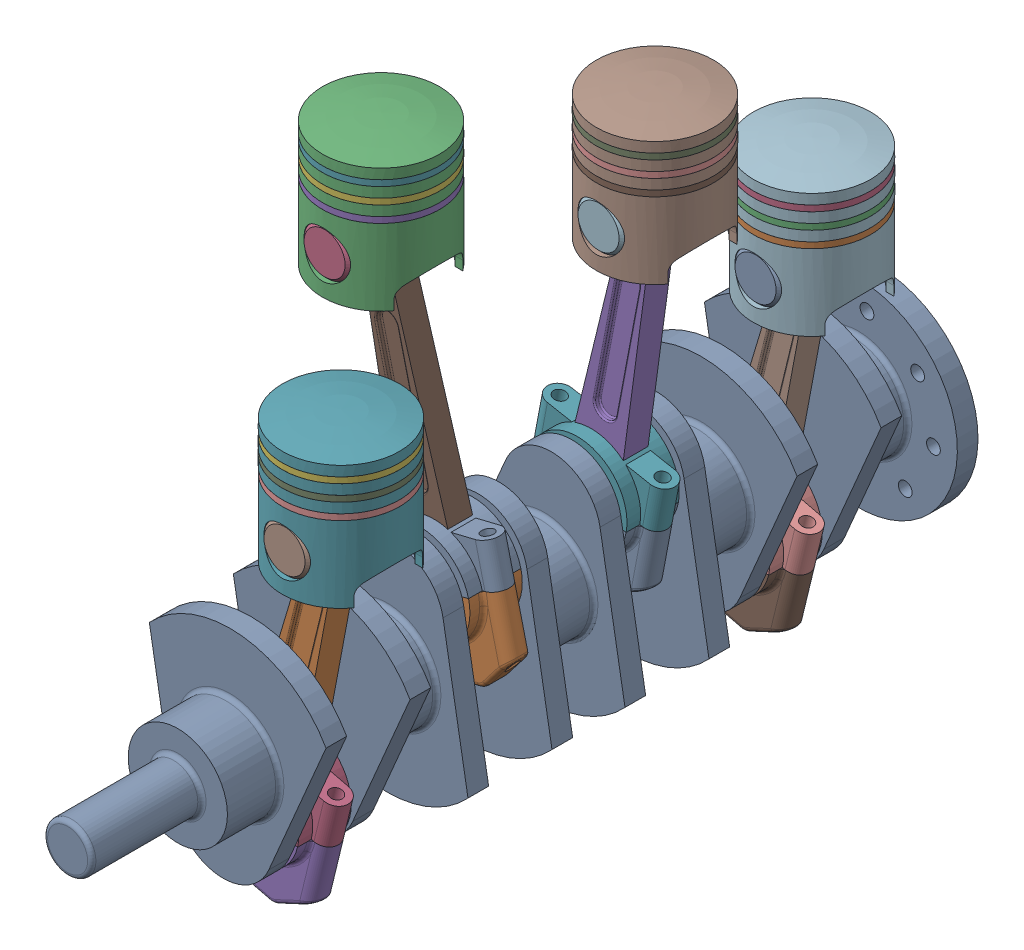
SolidWorks assembly engine, configuration Default. Lengths in mm.
Overall size (200.17 422.52 589).
29 component instances, 6 part files, 66 mates.
Components (placement in the parent):
- crankshaft-1: crankshaft [Default] at (0 0 454) x (0.993296 -0.115595 0) z (0 0 1) size (144 160 589)
- centerline-1: centerline [Default] at (42.4529 151.7981 431) x (0.971686 -0.236278 0) z (0 0 1) size (94 223.7 38)
- connecting rod cap-1: connecting rod cap [Default] at (-5.0862 -43.705 431) x (-0.971686 0.236278 0) z (0 0 1) size (94 60 38)
- engine ring-1: engine ring [Default] at (42.4529 203.1981 431) size (85 4.3 85)
- engine1-1: engine1 [Default] at (42.4529 124.7981 431) size (85 95 85)
- piston pin-1: piston pin [Default] at (42.4529 151.7981 431) size (33.8 33.8 82)
- engine ring-3: engine ring [Default] at (42.4529 191.5981 431) x (0.460546 0 -0.887636) z (0.887636 0 0.460546) size (85 4.3 85)
- engine ring-5: engine ring [Default] at (42.4529 179.9981 431) x (0.546944 0 -0.837169) z (0.837169 0 0.546944) size (85 4.3 85)
- centerline-3: centerline [Default] at (-42.4529 239.2082 317) x (0.971686 0.236278 0) z (0 0 1) size (94 223.7 38)
- connecting rod cap-3: connecting rod cap [Default] at (5.0862 43.705 317) x (-0.971686 -0.236278 0) z (0 0 1) size (94 60 38)
- engine1-3: engine1 [Default] at (-42.4529 212.2082 317) size (85 95 85)
- piston pin-3: piston pin [Default] at (-42.4529 239.2082 317) x (0.987351 0.158553 0) z (0 0 1) size (33.8 33.8 82)
- engine ring-6: engine ring [Default] at (-42.4529 267.4082 317) x (0.392049 0 -0.919944) z (0.919944 0 0.392049) size (85 4.3 85)
- engine ring-7: engine ring [Default] at (-42.4529 279.0082 317) x (0.298154 0 -0.954518) z (0.954518 0 0.298154) size (85 4.3 85)
- engine ring-8: engine ring [Default] at (-42.4529 290.6082 317) x (0.984578 0 -0.174947) z (0.174947 0 0.984578) size (85 4.3 85)
- centerline-9: centerline [Default] at (42.4529 151.7981 89) x (-0.971686 0.236278 0) z (0 0 -1) size (94 223.7 38)
- connecting rod cap-9: connecting rod cap [Default] at (-5.0862 -43.705 89) x (0.971686 -0.236278 0) z (0 0 -1) size (94 60 38)
- engine1-9: engine1 [Default] at (42.4529 124.7981 89) x (-1 0 0) z (0 0 -1) size (85 95 85)
- piston pin-9: piston pin [Default] at (42.4529 151.7981 89) x (-0.5 0.866025 0) z (0 0 -1) size (33.8 33.8 82)
- engine ring-24: engine ring [Default] at (42.4529 179.9981 89) x (-0.341569 0 -0.939857) z (0.939857 0 -0.341569) size (85 4.3 85)
- engine ring-25: engine ring [Default] at (42.4529 191.5981 89) x (-0.433781 0 -0.901018) z (0.901018 0 -0.433781) size (85 4.3 85)
- engine ring-26: engine ring [Default] at (42.4529 203.1981 89) x (0.6 0 -0.8) z (0.8 0 0.6) size (85 4.3 85)
- centerline-10: centerline [Default] at (42.4529 241.4047 203) x (-0.982603 0.185719 0) z (0 0 -1) size (94 223.7 38)
- engine1-10: engine1 [Default] at (42.4529 214.4047 203) x (-1 0 0) z (0 0 -1) size (85 95 85)
- engine ring-27: engine ring [Default] at (42.4529 292.8047 203) x (0.941458 0 -0.337131) z (0.337131 0 0.941458) size (85 4.3 85)
- engine ring-28: engine ring [Default] at (42.4529 281.2047 203) x (0.134335 0 -0.990936) z (0.990936 0 0.134335) size (85 4.3 85)
- engine ring-29: engine ring [Default] at (42.4529 269.6047 203) x (0.23269 0 -0.972551) z (0.972551 0 0.23269) size (85 4.3 85)
- piston pin-10: piston pin [Default] at (42.4529 241.4047 203) x (-0.173648 0.984808 0) z (0 0 -1) size (33.8 33.8 82)
- connecting rod cap-10: connecting rod cap [Default] at (5.0862 43.705 203) x (0.982603 -0.185719 0) z (0 0 -1) size (94 60 38)
Mates (geometry in assembly coordinates):
- Concentric1: concentric anti-aligned: cylinder of crankshaft-1 through (0 0 586.9999) axis (0 0 -1) radius 17.5
- Coincident2: coincident: plane of crankshaft-1 through (0 0 586.9999) normal (0 0 1)
- Coincident3: coincident aligned: plane of engine1-1 through (42.4529 124.8201 430.9999) normal (0 0 1); plane of piston pin-1 through (42.4529 151.8201 430.9999) normal (0 0 1)
- Concentric2: concentric anti-aligned: cylinder of engine1-1 through (42.4529 151.8201 388.4999) axis (0 0 1) radius 16.9; cylinder of piston pin-1 through (42.4529 151.8201 471.9999) axis (0 0 -1) radius 16.9
- Concentric3: concentric aligned: cylinder of engine ring-1 through (42.4529 207.5201 430.9999) axis (0 -1 0) radius 42.5; cylinder of engine1-1 through (42.4529 214.8201 430.9999) axis (0 -1 0) radius 42.5
- Coincident4: coincident anti-aligned: plane of engine ring-1 through (42.4529 203.2201 430.9999) normal (0 -1 0); plane of engine1-1 through (42.4529 203.2201 430.9999) normal (0 1 0)
- Concentric5: concentric anti-aligned: cylinder of engine1-1 through (42.4529 191.6201 430.9999) axis (0 1 0) radius 39.5; cylinder of engine ring-3 through (42.4529 195.9201 430.9999) axis (0 -1 0) radius 42.5
- Coincident5: coincident anti-aligned: plane of engine1-1 through (42.4529 191.6201 430.9999) normal (0 1 0); plane of engine ring-3 through (42.4529 191.6201 430.9999) normal (0 -1 0)
- Concentric6: concentric anti-aligned: cylinder of engine1-1 through (42.4529 180.0201 430.9999) axis (0 1 0) radius 39.5; cylinder of engine ring-5 through (42.4529 184.3201 430.9999) axis (0 -1 0) radius 42.5
- Coincident6: coincident anti-aligned: plane of engine1-1 through (42.4529 180.0201 430.9999) normal (0 1 0); plane of engine ring-5 through (42.4529 180.0201 430.9999) normal (0 -1 0)
- Coincident7: coincident aligned: plane of centerline-1 through (42.4529 151.8201 430.9999) normal (0 0 1); plane of engine1-1 through (42.4529 124.8201 430.9999) normal (0 0 1)
- Concentric7: concentric aligned: cylinder of centerline-1 through (42.4529 151.8201 449.9999) axis (0 0 -1) radius 16.9; cylinder of piston pin-1 through (42.4529 151.8201 471.9999) axis (0 0 -1) radius 16.9
- Concentric8: concentric aligned: cylinder of centerline-1 through (32.0169 -52.6708 430.9999) axis (0.235427 0.971892 0) radius 4.5; cylinder of connecting rod cap-1 through (17.8913 -110.9843 430.9999) axis (0.235427 0.971892 0) radius 4.5
- Concentric10: concentric aligned: cylinder of centerline-1 through (-41.8469 -34.7784 430.9999) axis (0.235427 0.971892 0) radius 4.5; cylinder of connecting rod cap-1 through (-55.9725 -93.0919 430.9999) axis (0.235427 0.971892 0) radius 4.5
- Coincident8: coincident anti-aligned: plane of centerline-1; plane of connecting rod cap-1
- Width1: width aligned: plane of crankshaft-1 through (-4.915 -43.7246 407.9999) normal (0 0 1); plane of centerline-1 through (-4.915 -43.7246 453.9999) normal (0 0 -1); plane of crankshaft-1 through (42.4529 151.8201 439.9999) normal (0 0 1); plane of centerline-1 through (42.4529 151.8201 421.9999) normal (0 0 -1)
- Concentric11: concentric anti-aligned: cylinder of crankshaft-1 through (-4.915 -43.7246 407.9999) axis (0 0 1) radius 27; cylinder of connecting rod cap-1 through (-4.915 -43.7246 449.9999) axis (0 0 -1) radius 27
- Coincident12: coincident: cylinder of engine1-1 through (42.4529 214.8201 430.9999) axis (0 -1 0) radius 42.5
- Coincident18: coincident aligned: plane of engine1-3 through (-42.4529 212.2694 316.9999) normal (0 0 1); plane of piston pin-3 through (-42.4529 239.2694 316.9999) normal (0 0 1)
- Concentric23: concentric anti-aligned: cylinder of engine1-3 through (-42.4529 239.2694 274.4999) axis (0 0 1) radius 16.9; cylinder of piston pin-3 through (-42.4529 239.2694 357.9999) axis (0 0 -1) radius 16.9
- Concentric24: concentric aligned: cylinder of engine1-3 through (-42.4529 302.2694 316.9999) axis (0 -1 0) radius 42.5; cylinder of engine ring-8 through (-42.4529 294.9694 316.9999) axis (0 -1 0) radius 42.5
- Coincident19: coincident anti-aligned: plane of engine1-3 through (-42.4529 290.6694 316.9999) normal (0 1 0); plane of engine ring-8 through (-42.4529 290.6694 316.9999) normal (0 -1 0)
- Concentric25: concentric anti-aligned: cylinder of engine1-3 through (-42.4529 279.0694 316.9999) axis (0 1 0) radius 39.5; cylinder of engine ring-7 through (-42.4529 283.3694 316.9999) axis (0 -1 0) radius 42.5
- Coincident20: coincident anti-aligned: plane of engine1-3 through (-42.4529 279.0694 316.9999) normal (0 1 0); plane of engine ring-7 through (-42.4529 279.0694 316.9999) normal (0 -1 0)
- Concentric26: concentric anti-aligned: cylinder of engine1-3 through (-42.4529 267.4694 316.9999) axis (0 1 0) radius 39.5; cylinder of engine ring-6 through (-42.4529 271.7694 316.9999) axis (0 -1 0) radius 42.5
- Coincident21: coincident anti-aligned: plane of engine1-3 through (-42.4529 267.4694 316.9999) normal (0 1 0); plane of engine ring-6 through (-42.4529 267.4694 316.9999) normal (0 -1 0)
- Coincident22: coincident aligned: plane of centerline-3 through (-42.4529 239.2694 316.9999) normal (0 0 1); plane of engine1-3 through (-42.4529 212.2694 316.9999) normal (0 0 1)
- Concentric27: concentric aligned: cylinder of centerline-3 through (-42.4529 239.2694 335.9999) axis (0 0 -1) radius 16.9; cylinder of piston pin-3 through (-42.4529 239.2694 357.9999) axis (0 0 -1) radius 16.9
- Concentric28: concentric aligned: cylinder of centerline-3 through (41.8469 52.6709 316.9999) axis (-0.235427 0.971892 0) radius 4.5; cylinder of connecting rod cap-3 through (55.9725 -5.6426 316.9999) axis (-0.235427 0.971892 0) radius 4.5
- Concentric29: concentric aligned: cylinder of centerline-3 through (-32.0169 34.7784 316.9999) axis (-0.235427 0.971892 0) radius 4.5; cylinder of connecting rod cap-3 through (-17.8913 -23.5351 316.9999) axis (-0.235427 0.971892 0) radius 4.5
- Coincident23: coincident anti-aligned: plane of centerline-3; plane of connecting rod cap-3
- Width2: width aligned: plane of crankshaft-1 through (4.915 43.7247 293.9999) normal (0 0 1); plane of crankshaft-1 through (4.915 43.7247 339.9999) normal (0 0 -1); plane of centerline-3 through (-42.4529 239.2694 325.9999) normal (0 0 1); plane of centerline-3 through (-42.4529 239.2694 307.9999) normal (0 0 -1)
- Concentric30: concentric anti-aligned: cylinder of crankshaft-1 through (4.915 43.7247 293.9999) axis (0 0 1) radius 27; cylinder of connecting rod cap-3 through (4.915 43.7247 335.9999) axis (0 0 -1) radius 27
- Coincident24: coincident: cylinder of engine1-3 through (-42.4529 302.2694 316.9999) axis (0 -1 0) radius 42.5
- Coincident56: coincident aligned: plane of engine1-9 through (42.4529 124.8201 88.9999) normal (0 0 -1); plane of piston pin-9 through (42.4529 151.8201 88.9999) normal (0 0 -1)
- Concentric67: concentric anti-aligned: cylinder of engine1-9 through (42.4529 151.8201 131.4999) axis (0 0 -1) radius 16.9; cylinder of piston pin-9 through (42.4529 151.8201 47.9999) axis (0 0 1) radius 16.9
- Concentric68: concentric aligned: cylinder of engine1-9 through (42.4529 214.8201 88.9999) axis (0 -1 0) radius 42.5; cylinder of engine ring-26 through (42.4529 207.5201 88.9999) axis (0 -1 0) radius 42.5
- Coincident57: coincident anti-aligned: plane of engine1-9 through (42.4529 203.2201 88.9999) normal (0 1 0); plane of engine ring-26 through (42.4529 203.2201 88.9999) normal (0 -1 0)
- Concentric69: concentric anti-aligned: cylinder of engine1-9 through (42.4529 191.6201 88.9999) axis (0 1 0) radius 39.5; cylinder of engine ring-25 through (42.4529 195.9201 88.9999) axis (0 -1 0) radius 42.5
- Coincident58: coincident anti-aligned: plane of engine1-9 through (42.4529 191.6201 88.9999) normal (0 1 0); plane of engine ring-25 through (42.4529 191.6201 88.9999) normal (0 -1 0)
- Concentric70: concentric anti-aligned: cylinder of engine1-9 through (42.4529 180.0201 88.9999) axis (0 1 0) radius 39.5; cylinder of engine ring-24 through (42.4529 184.3201 88.9999) axis (0 -1 0) radius 42.5
- Coincident59: coincident anti-aligned: plane of engine1-9 through (42.4529 180.0201 88.9999) normal (0 1 0); plane of engine ring-24 through (42.4529 180.0201 88.9999) normal (0 -1 0)
- Coincident60: coincident aligned: plane of centerline-9 through (42.4529 151.8201 88.9999) normal (0 0 -1); plane of engine1-9 through (42.4529 124.8201 88.9999) normal (0 0 -1)
- Concentric71: concentric aligned: cylinder of centerline-9 through (42.4529 151.8201 69.9999) axis (0 0 1) radius 16.9; cylinder of piston pin-9 through (42.4529 151.8201 47.9999) axis (0 0 1) radius 16.9
- Concentric72: concentric aligned: cylinder of centerline-9 through (-41.8469 -34.7784 88.9999) axis (0.235427 0.971892 0) radius 4.5; cylinder of connecting rod cap-9 through (-55.9725 -93.0919 88.9999) axis (0.235427 0.971892 0) radius 4.5
- Concentric73: concentric aligned: cylinder of centerline-9 through (32.0169 -52.6708 88.9999) axis (0.235427 0.971892 0) radius 4.5; cylinder of connecting rod cap-9 through (17.8913 -110.9843 88.9999) axis (0.235427 0.971892 0) radius 4.5
- Coincident61: coincident anti-aligned: plane of centerline-9; plane of connecting rod cap-9
- Concentric74: concentric anti-aligned: cylinder of crankshaft-1 through (-4.915 -43.7246 111.9999) axis (0 0 -1) radius 27; cylinder of connecting rod cap-9 through (-4.915 -43.7246 69.9999) axis (0 0 1) radius 27
- Coincident62: coincident: cylinder of engine1-9 through (42.4529 214.8201 88.9999) axis (0 -1 0) radius 42.5
- Width6: width aligned: plane of crankshaft-1 through (-4.915 -43.7246 65.9999) normal (0 0 1); plane of crankshaft-1 through (-4.915 -43.7246 111.9999) normal (0 0 -1); plane of centerline-9 through (42.4529 151.8201 79.9999) normal (0 0 -1); plane of centerline-9 through (42.4529 151.8201 97.9999) normal (0 0 1)
- Coincident63: coincident aligned: plane of engine1-10 through (42.4529 214.3919 202.9999) normal (0 0 -1); plane of piston pin-10 through (42.4529 241.3919 202.9999) normal (0 0 -1)
- Concentric75: concentric anti-aligned: cylinder of engine1-10 through (42.4529 241.3919 245.4999) axis (0 0 -1) radius 16.9; cylinder of piston pin-10 through (42.4529 241.3919 161.9999) axis (0 0 1) radius 16.9
- Concentric76: concentric aligned: cylinder of engine1-10 through (42.4529 304.3919 202.9999) axis (0 -1 0) radius 42.5; cylinder of engine ring-27 through (42.4529 297.0919 202.9999) axis (0 -1 0) radius 42.5
- Coincident64: coincident anti-aligned: plane of engine1-10 through (42.4529 292.7919 202.9999) normal (0 1 0); plane of engine ring-27 through (42.4529 292.7919 202.9999) normal (0 -1 0)
- Concentric77: concentric anti-aligned: cylinder of engine1-10 through (42.4529 281.1919 202.9999) axis (0 1 0) radius 39.5; cylinder of engine ring-28 through (42.4529 285.4919 202.9999) axis (0 -1 0) radius 42.5
- Coincident65: coincident anti-aligned: plane of engine1-10 through (42.4529 281.1919 202.9999) normal (0 1 0); plane of engine ring-28 through (42.4529 281.1919 202.9999) normal (0 -1 0)
- Concentric78: concentric anti-aligned: cylinder of engine1-10 through (42.4529 269.5919 202.9999) axis (0 1 0) radius 39.5; cylinder of engine ring-29 through (42.4529 273.8919 202.9999) axis (0 -1 0) radius 42.5
- Coincident66: coincident anti-aligned: plane of engine1-10 through (42.4529 269.5919 202.9999) normal (0 1 0); plane of engine ring-29 through (42.4529 269.5919 202.9999) normal (0 -1 0)
- Coincident67: coincident aligned: plane of centerline-10 through (42.4529 241.3919 202.9999) normal (0 0 -1); plane of engine1-10 through (42.4529 214.3919 202.9999) normal (0 0 -1)
- Concentric79: concentric aligned: cylinder of centerline-10 through (42.4529 241.3919 183.9999) axis (0 0 1) radius 16.9; cylinder of piston pin-10 through (42.4529 241.3919 161.9999) axis (0 0 1) radius 16.9
- Concentric80: concentric aligned: cylinder of centerline-10 through (-32.4178 50.8143 202.9999) axis (0.18657 0.982442 0) radius 4.5; cylinder of connecting rod cap-10 through (-43.612 -8.1322 202.9999) axis (0.18657 0.982442 0) radius 4.5
- Concentric81: concentric aligned: cylinder of centerline-10 through (42.2478 36.635 202.9999) axis (0.18657 0.982442 0) radius 4.5; cylinder of connecting rod cap-10 through (31.0535 -22.3115 202.9999) axis (0.18657 0.982442 0) radius 4.5
- Coincident68: coincident anti-aligned: plane of centerline-10; plane of connecting rod cap-10
- Width7: width aligned: plane of crankshaft-1 through (4.915 43.7247 225.9999) normal (0 0 -1); plane of centerline-10 through (4.915 43.7247 179.9999) normal (0 0 1); plane of crankshaft-1 through (42.4529 241.3919 193.9999) normal (0 0 -1); plane of centerline-10 through (42.4529 241.3919 211.9999) normal (0 0 1)
- Concentric82: concentric anti-aligned: cylinder of crankshaft-1 through (4.915 43.7247 225.9999) axis (0 0 -1) radius 27; cylinder of connecting rod cap-10 through (4.915 43.7247 183.9999) axis (0 0 1) radius 27
- Coincident69: coincident: cylinder of engine1-10 through (42.4529 304.3919 202.9999) axis (0 -1 0) radius 42.5
